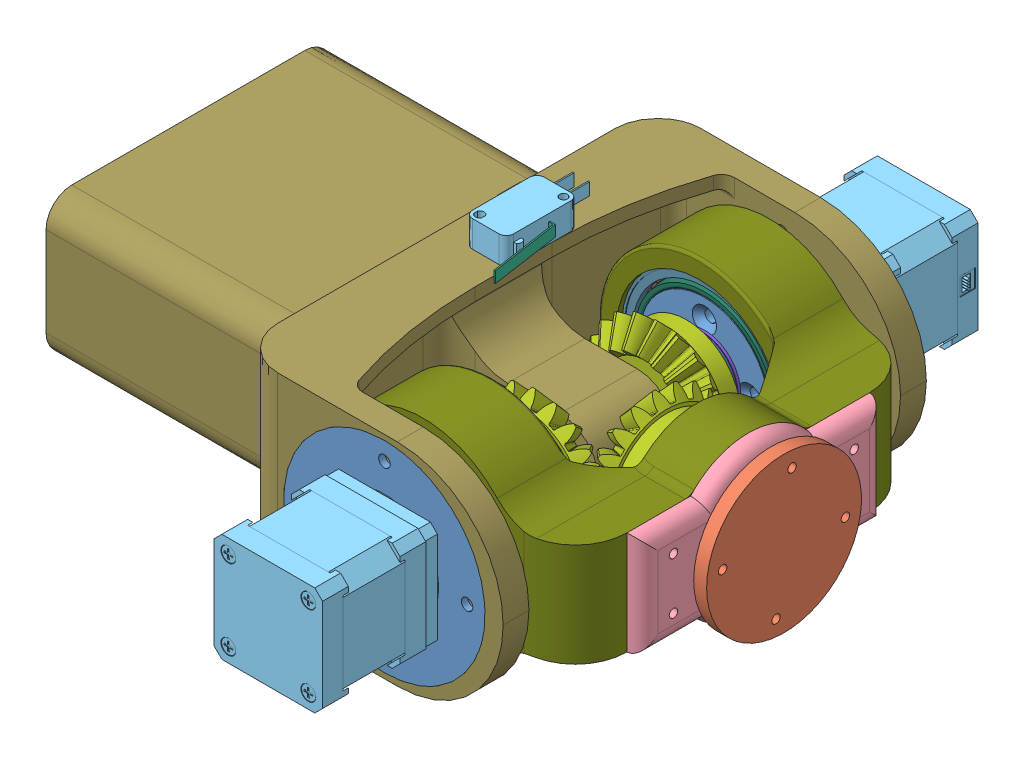
SolidWorks assembly Wrist assembly v4, configuration Default. Lengths in mm.
Overall size (231 102.6 254).
236 component instances, 25 part files, 63 mates.
Components (placement in the parent):
- Motor sleeve-1: Motor sleeve [Default] at (57.5488 50.2907 113.4481) x (0 0 -1) z (1 0 0) size (40 78 78)
- Motor sleeve-2: Motor sleeve [Default] at (57.5488 50.2907 -50.5519) x (0 0 1) z (-1 0 0) size (40 78 78)
- HK_1412-1: HK_1412 [Default] at (57.5488 50.2907 46.4481) x (0 0 -1) z (0.911021 -0.412359 0) size (12 20 20)
  - HK_1412_3-1: HK_1412_3 [Default] x (1 0 0) z (0 -0.382683 0.92388) size (7.3 2 2)
  - HK_1412_3-2: HK_1412_3 [Default] x (1 0 0) z (0 -0.707107 0.707107) size (7.3 2 2)
  - HK_1412_3-3: HK_1412_3 [Default] x (1 0 0) z (0 -0.92388 0.382683) size (7.3 2 2)
  - HK_1412_3-4: HK_1412_3 [Default] x (1 0 0) z (0 -1 0) size (7.3 2 2)
  - HK_1412_3-5: HK_1412_3 [Default] x (1 0 0) z (0 -0.92388 -0.382683) size (7.3 2 2)
  - HK_1412_3-6: HK_1412_3 [Default] x (1 0 0) z (0 -0.707107 -0.707107) size (7.3 2 2)
  - HK_1412_3-7: HK_1412_3 [Default] x (1 0 0) z (0 -0.382683 -0.92388) size (7.3 2 2)
  - HK_1412_3-8: HK_1412_3 [Default] x (1 0 0) z (0 0 -1) size (7.3 2 2)
  - HK_1412_3-9: HK_1412_3 [Default] x (1 0 0) z (0 0.382683 -0.92388) size (7.3 2 2)
  - HK_1412_3-10: HK_1412_3 [Default] x (1 0 0) z (0 0.707107 -0.707107) size (7.3 2 2)
  - HK_1412_3-11: HK_1412_3 [Default] x (1 0 0) z (0 0.92388 -0.382683) size (7.3 2 2)
  - HK_1412_3-12: HK_1412_3 [Default] x (1 0 0) z (0 1 0) size (7.3 2 2)
  - HK_1412_3-13: HK_1412_3 [Default] x (1 0 0) z (0 0.92388 0.382683) size (7.3 2 2)
  - HK_1412_3-14: HK_1412_3 [Default] x (1 0 0) z (0 0.707107 0.707107) size (7.3 2 2)
  - HK_1412_3-15: HK_1412_3 [Default] x (1 0 0) z (0 0.382683 0.92388) size (7.3 2 2)
  - HK_1412_3-16: HK_1412_3 [Default] at origin size (7.3 2 2)
  - HK_1412_20-1: HK_1412_20 [Default] x (1 0 0) z (0 -0.382683 0.92388) size (7.3 2 2)
  - HK_1412_20-2: HK_1412_20 [Default] x (1 0 0) z (0 -0.707107 0.707107) size (7.3 2 2)
  - HK_1412_20-3: HK_1412_20 [Default] x (1 0 0) z (0 -0.92388 0.382683) size (7.3 2 2)
  - HK_1412_20-4: HK_1412_20 [Default] x (1 0 0) z (0 -1 0) size (7.3 2 2)
  - HK_1412_20-5: HK_1412_20 [Default] x (1 0 0) z (0 -0.92388 -0.382683) size (7.3 2 2)
  - HK_1412_20-6: HK_1412_20 [Default] x (1 0 0) z (0 -0.707107 -0.707107) size (7.3 2 2)
  - HK_1412_20-7: HK_1412_20 [Default] x (1 0 0) z (0 -0.382683 -0.92388) size (7.3 2 2)
  - HK_1412_20-8: HK_1412_20 [Default] x (1 0 0) z (0 0 -1) size (7.3 2 2)
  - HK_1412_20-9: HK_1412_20 [Default] x (1 0 0) z (0 0.382683 -0.92388) size (7.3 2 2)
  - HK_1412_20-10: HK_1412_20 [Default] x (1 0 0) z (0 0.707107 -0.707107) size (7.3 2 2)
  - HK_1412_20-11: HK_1412_20 [Default] x (1 0 0) z (0 0.92388 -0.382683) size (7.3 2 2)
  - HK_1412_20-12: HK_1412_20 [Default] x (1 0 0) z (0 1 0) size (7.3 2 2)
  - HK_1412_20-13: HK_1412_20 [Default] x (1 0 0) z (0 0.92388 0.382683) size (7.3 2 2)
  - HK_1412_20-14: HK_1412_20 [Default] x (1 0 0) z (0 0.707107 0.707107) size (7.3 2 2)
  - HK_1412_20-15: HK_1412_20 [Default] x (1 0 0) z (0 0.382683 0.92388) size (7.3 2 2)
  - HK_1412_20-16: HK_1412_20 [Default] at origin size (7.3 2 2)
  - HK_1412_37-1: HK_1412_37 [Default] at origin size (12 20 20)
- HK_1412-2: HK_1412 [Default] at (57.5488 50.2907 28.4481) x (0 0 -1) z (0.122911 0.992418 0) size (12 20 20)
  - HK_1412_3-1: HK_1412_3 [Default] x (1 0 0) z (0 -0.382683 0.92388) size (7.3 2 2)
  - HK_1412_3-2: HK_1412_3 [Default] x (1 0 0) z (0 -0.707107 0.707107) size (7.3 2 2)
  - HK_1412_3-3: HK_1412_3 [Default] x (1 0 0) z (0 -0.92388 0.382683) size (7.3 2 2)
  - HK_1412_3-4: HK_1412_3 [Default] x (1 0 0) z (0 -1 0) size (7.3 2 2)
  - HK_1412_3-5: HK_1412_3 [Default] x (1 0 0) z (0 -0.92388 -0.382683) size (7.3 2 2)
  - HK_1412_3-6: HK_1412_3 [Default] x (1 0 0) z (0 -0.707107 -0.707107) size (7.3 2 2)
  - HK_1412_3-7: HK_1412_3 [Default] x (1 0 0) z (0 -0.382683 -0.92388) size (7.3 2 2)
  - HK_1412_3-8: HK_1412_3 [Default] x (1 0 0) z (0 0 -1) size (7.3 2 2)
  - HK_1412_3-9: HK_1412_3 [Default] x (1 0 0) z (0 0.382683 -0.92388) size (7.3 2 2)
  - HK_1412_3-10: HK_1412_3 [Default] x (1 0 0) z (0 0.707107 -0.707107) size (7.3 2 2)
  - HK_1412_3-11: HK_1412_3 [Default] x (1 0 0) z (0 0.92388 -0.382683) size (7.3 2 2)
  - HK_1412_3-12: HK_1412_3 [Default] x (1 0 0) z (0 1 0) size (7.3 2 2)
  - HK_1412_3-13: HK_1412_3 [Default] x (1 0 0) z (0 0.92388 0.382683) size (7.3 2 2)
  - HK_1412_3-14: HK_1412_3 [Default] x (1 0 0) z (0 0.707107 0.707107) size (7.3 2 2)
  - HK_1412_3-15: HK_1412_3 [Default] x (1 0 0) z (0 0.382683 0.92388) size (7.3 2 2)
  - HK_1412_3-16: HK_1412_3 [Default] at origin size (7.3 2 2)
  - HK_1412_20-1: HK_1412_20 [Default] x (1 0 0) z (0 -0.382683 0.92388) size (7.3 2 2)
  - HK_1412_20-2: HK_1412_20 [Default] x (1 0 0) z (0 -0.707107 0.707107) size (7.3 2 2)
  - HK_1412_20-3: HK_1412_20 [Default] x (1 0 0) z (0 -0.92388 0.382683) size (7.3 2 2)
  - HK_1412_20-4: HK_1412_20 [Default] x (1 0 0) z (0 -1 0) size (7.3 2 2)
  - HK_1412_20-5: HK_1412_20 [Default] x (1 0 0) z (0 -0.92388 -0.382683) size (7.3 2 2)
  - HK_1412_20-6: HK_1412_20 [Default] x (1 0 0) z (0 -0.707107 -0.707107) size (7.3 2 2)
  - HK_1412_20-7: HK_1412_20 [Default] x (1 0 0) z (0 -0.382683 -0.92388) size (7.3 2 2)
  - HK_1412_20-8: HK_1412_20 [Default] x (1 0 0) z (0 0 -1) size (7.3 2 2)
  - HK_1412_20-9: HK_1412_20 [Default] x (1 0 0) z (0 0.382683 -0.92388) size (7.3 2 2)
  - HK_1412_20-10: HK_1412_20 [Default] x (1 0 0) z (0 0.707107 -0.707107) size (7.3 2 2)
  - HK_1412_20-11: HK_1412_20 [Default] x (1 0 0) z (0 0.92388 -0.382683) size (7.3 2 2)
  - HK_1412_20-12: HK_1412_20 [Default] x (1 0 0) z (0 1 0) size (7.3 2 2)
  - HK_1412_20-13: HK_1412_20 [Default] x (1 0 0) z (0 0.92388 0.382683) size (7.3 2 2)
  - HK_1412_20-14: HK_1412_20 [Default] x (1 0 0) z (0 0.707107 0.707107) size (7.3 2 2)
  - HK_1412_20-15: HK_1412_20 [Default] x (1 0 0) z (0 0.382683 0.92388) size (7.3 2 2)
  - HK_1412_20-16: HK_1412_20 [Default] at origin size (7.3 2 2)
  - HK_1412_37-1: HK_1412_37 [Default] at origin size (12 20 20)
- 17HS15-1684D-HG10-AR3-2: 17HS15-1684D-HG10-AR3 [Default] at (57.5488 50.2907 -55.5519) size (42.88 42 103.5)
- 17HS15-1684D-HG10-AR3-3: 17HS15-1684D-HG10-AR3 [Default] at (57.5488 50.2907 118.4481) x (-1 0 0) z (0 0 -1) size (42.88 42 103.5)
- shaft-1: shaft [Default] at (57.5488 50.2907 -12.0519) x (0 0 1) z (0.708325 0.705887 0) size (42 17 17)
- shaft-2: shaft [Default] at (57.5488 50.2907 74.9481) x (0 0 -1) z (-0.905823 0.423655 0) size (42 17 17)
- AXK_1528___AS_1528___AS_1528-2: AXK_1528___AS_1528___AS_1528 [Default] at (57.5488 50.2907 71.4481) x (0 0 -1) z (0.812919 0.582377 0) size (4 28 28)
  - AXK_1528___AS_1528___AS_1528_3-1: AXK_1528___AS_1528___AS_1528_3 [Default] x (1 0 0) z (0 -0.309017 0.951057) size (2 5 2)
  - AXK_1528___AS_1528___AS_1528_3-2: AXK_1528___AS_1528___AS_1528_3 [Default] x (1 0 0) z (0 -0.587785 0.809017) size (2 5 2)
  - AXK_1528___AS_1528___AS_1528_3-3: AXK_1528___AS_1528___AS_1528_3 [Default] x (1 0 0) z (0 -0.809017 0.587785) size (2 5 2)
  - AXK_1528___AS_1528___AS_1528_3-4: AXK_1528___AS_1528___AS_1528_3 [Default] x (1 0 0) z (0 -0.951057 0.309017) size (2 5 2)
  - AXK_1528___AS_1528___AS_1528_3-5: AXK_1528___AS_1528___AS_1528_3 [Default] x (1 0 0) z (0 -1 0) size (2 5 2)
  - AXK_1528___AS_1528___AS_1528_3-6: AXK_1528___AS_1528___AS_1528_3 [Default] x (1 0 0) z (0 -0.951057 -0.309017) size (2 5 2)
  - AXK_1528___AS_1528___AS_1528_3-7: AXK_1528___AS_1528___AS_1528_3 [Default] x (1 0 0) z (0 -0.809017 -0.587785) size (2 5 2)
  - AXK_1528___AS_1528___AS_1528_3-8: AXK_1528___AS_1528___AS_1528_3 [Default] x (1 0 0) z (0 -0.587785 -0.809017) size (2 5 2)
  - AXK_1528___AS_1528___AS_1528_3-9: AXK_1528___AS_1528___AS_1528_3 [Default] x (1 0 0) z (0 -0.309017 -0.951057) size (2 5 2)
  - AXK_1528___AS_1528___AS_1528_3-10: AXK_1528___AS_1528___AS_1528_3 [Default] x (1 0 0) z (0 0 -1) size (2 5 2)
  - AXK_1528___AS_1528___AS_1528_3-11: AXK_1528___AS_1528___AS_1528_3 [Default] x (1 0 0) z (0 0.309017 -0.951057) size (2 5 2)
  - AXK_1528___AS_1528___AS_1528_3-12: AXK_1528___AS_1528___AS_1528_3 [Default] x (1 0 0) z (0 0.587785 -0.809017) size (2 5 2)
  - AXK_1528___AS_1528___AS_1528_3-13: AXK_1528___AS_1528___AS_1528_3 [Default] x (1 0 0) z (0 0.809017 -0.587785) size (2 5 2)
  - AXK_1528___AS_1528___AS_1528_3-14: AXK_1528___AS_1528___AS_1528_3 [Default] x (1 0 0) z (0 0.951057 -0.309017) size (2 5 2)
  - AXK_1528___AS_1528___AS_1528_3-15: AXK_1528___AS_1528___AS_1528_3 [Default] x (1 0 0) z (0 1 0) size (2 5 2)
  - AXK_1528___AS_1528___AS_1528_3-16: AXK_1528___AS_1528___AS_1528_3 [Default] x (1 0 0) z (0 0.951057 0.309017) size (2 5 2)
  - AXK_1528___AS_1528___AS_1528_3-17: AXK_1528___AS_1528___AS_1528_3 [Default] x (1 0 0) z (0 0.809017 0.587785) size (2 5 2)
  - AXK_1528___AS_1528___AS_1528_3-18: AXK_1528___AS_1528___AS_1528_3 [Default] x (1 0 0) z (0 0.587785 0.809017) size (2 5 2)
  - AXK_1528___AS_1528___AS_1528_3-19: AXK_1528___AS_1528___AS_1528_3 [Default] x (1 0 0) z (0 0.309017 0.951057) size (2 5 2)
  - AXK_1528___AS_1528___AS_1528_3-20: AXK_1528___AS_1528___AS_1528_3 [Default] at origin size (2 5 2)
  - AXK_1528___AS_1528___AS_1528_24-1: AXK_1528___AS_1528___AS_1528_24 [Default] at origin size (1 28 28)
  - AXK_1528___AS_1528___AS_1528_26-1: AXK_1528___AS_1528___AS_1528_26 [Default] at origin size (1 28 28)
  - AXK_1528___AS_1528___AS_1528_28-1: AXK_1528___AS_1528___AS_1528_28 [Default] at origin size (1.6 28 28)
- 2mm spacer-1: 2mm spacer [Default] at (57.5488 50.2907 66.4481) x (0.999741 0.022777 0) z (0 0 1) size (28 28 1.5)
- AXK_1528___AS_1528___AS_1528-3: AXK_1528___AS_1528___AS_1528 [Default] at (57.5488 50.2907 -8.5519) x (0 0 -1) z (0.999526 -0.030788 0) size (4 28 28)
  - AXK_1528___AS_1528___AS_1528_3-1: AXK_1528___AS_1528___AS_1528_3 [Default] x (1 0 0) z (0 -0.309017 0.951057) size (2 5 2)
  - AXK_1528___AS_1528___AS_1528_3-2: AXK_1528___AS_1528___AS_1528_3 [Default] x (1 0 0) z (0 -0.587785 0.809017) size (2 5 2)
  - AXK_1528___AS_1528___AS_1528_3-3: AXK_1528___AS_1528___AS_1528_3 [Default] x (1 0 0) z (0 -0.809017 0.587785) size (2 5 2)
  - AXK_1528___AS_1528___AS_1528_3-4: AXK_1528___AS_1528___AS_1528_3 [Default] x (1 0 0) z (0 -0.951057 0.309017) size (2 5 2)
  - AXK_1528___AS_1528___AS_1528_3-5: AXK_1528___AS_1528___AS_1528_3 [Default] x (1 0 0) z (0 -1 0) size (2 5 2)
  - AXK_1528___AS_1528___AS_1528_3-6: AXK_1528___AS_1528___AS_1528_3 [Default] x (1 0 0) z (0 -0.951057 -0.309017) size (2 5 2)
  - AXK_1528___AS_1528___AS_1528_3-7: AXK_1528___AS_1528___AS_1528_3 [Default] x (1 0 0) z (0 -0.809017 -0.587785) size (2 5 2)
  - AXK_1528___AS_1528___AS_1528_3-8: AXK_1528___AS_1528___AS_1528_3 [Default] x (1 0 0) z (0 -0.587785 -0.809017) size (2 5 2)
  - AXK_1528___AS_1528___AS_1528_3-9: AXK_1528___AS_1528___AS_1528_3 [Default] x (1 0 0) z (0 -0.309017 -0.951057) size (2 5 2)
  - AXK_1528___AS_1528___AS_1528_3-10: AXK_1528___AS_1528___AS_1528_3 [Default] x (1 0 0) z (0 0 -1) size (2 5 2)
  - AXK_1528___AS_1528___AS_1528_3-11: AXK_1528___AS_1528___AS_1528_3 [Default] x (1 0 0) z (0 0.309017 -0.951057) size (2 5 2)
  - AXK_1528___AS_1528___AS_1528_3-12: AXK_1528___AS_1528___AS_1528_3 [Default] x (1 0 0) z (0 0.587785 -0.809017) size (2 5 2)
  - AXK_1528___AS_1528___AS_1528_3-13: AXK_1528___AS_1528___AS_1528_3 [Default] x (1 0 0) z (0 0.809017 -0.587785) size (2 5 2)
  - AXK_1528___AS_1528___AS_1528_3-14: AXK_1528___AS_1528___AS_1528_3 [Default] x (1 0 0) z (0 0.951057 -0.309017) size (2 5 2)
  - AXK_1528___AS_1528___AS_1528_3-15: AXK_1528___AS_1528___AS_1528_3 [Default] x (1 0 0) z (0 1 0) size (2 5 2)
  - AXK_1528___AS_1528___AS_1528_3-16: AXK_1528___AS_1528___AS_1528_3 [Default] x (1 0 0) z (0 0.951057 0.309017) size (2 5 2)
  - AXK_1528___AS_1528___AS_1528_3-17: AXK_1528___AS_1528___AS_1528_3 [Default] x (1 0 0) z (0 0.809017 0.587785) size (2 5 2)
  - AXK_1528___AS_1528___AS_1528_3-18: AXK_1528___AS_1528___AS_1528_3 [Default] x (1 0 0) z (0 0.587785 0.809017) size (2 5 2)
  - AXK_1528___AS_1528___AS_1528_3-19: AXK_1528___AS_1528___AS_1528_3 [Default] x (1 0 0) z (0 0.309017 0.951057) size (2 5 2)
  - AXK_1528___AS_1528___AS_1528_3-20: AXK_1528___AS_1528___AS_1528_3 [Default] at origin size (2 5 2)
  - AXK_1528___AS_1528___AS_1528_24-1: AXK_1528___AS_1528___AS_1528_24 [Default] at origin size (1 28 28)
  - AXK_1528___AS_1528___AS_1528_26-1: AXK_1528___AS_1528___AS_1528_26 [Default] at origin size (1 28 28)
  - AXK_1528___AS_1528___AS_1528_28-1: AXK_1528___AS_1528___AS_1528_28 [Default] at origin size (1.6 28 28)
- 2mm spacer-2: 2mm spacer [Default] at (57.5488 50.2907 -5.0519) x (0.999526 -0.030788 0) z (0 0 1) size (28 28 1.5)
- Wrist input frame_combined-2: Wrist input frame_combined [Default] at (-20.9706 -62.2225 152.6176) x (-1 0 0) z (0 0 -1) size (204 82 164)
- NKI_50_25-1: NKI_50_25 [Default] at (57.5488 50.2907 -10.5519) x (0 0 -1) z (0.995738 -0.092229 0) size (25 68.42 68)
  - NKI_50_25_37-1: NKI_50_25_37 [Default] x (1 0 0) z (0 -0.189251 0.981929) size (18.8 3.5 3.5)
  - NKI_50_25_37-2: NKI_50_25_37 [Default] x (1 0 0) z (0 -0.371662 0.928368) size (18.8 3.5 3.5)
  - NKI_50_25_37-3: NKI_50_25_37 [Default] x (1 0 0) z (0 -0.540641 0.841254) size (18.8 3.5 3.5)
  - NKI_50_25_37-4: NKI_50_25_37 [Default] x (1 0 0) z (0 -0.690079 0.723734) size (18.8 3.5 3.5)
  - NKI_50_25_37-5: NKI_50_25_37 [Default] x (1 0 0) z (0 -0.814576 0.580057) size (18.8 3.5 3.5)
  - NKI_50_25_37-6: NKI_50_25_37 [Default] x (1 0 0) z (0 -0.909632 0.415415) size (18.8 3.5 3.5)
  - NKI_50_25_37-7: NKI_50_25_37 [Default] x (1 0 0) z (0 -0.971812 0.235759) size (18.8 3.5 3.5)
  - NKI_50_25_37-8: NKI_50_25_37 [Default] x (1 0 0) z (0 -0.998867 0.047582) size (18.8 3.5 3.5)
  - NKI_50_25_37-9: NKI_50_25_37 [Default] x (1 0 0) z (0 -0.989821 -0.142315) size (18.8 3.5 3.5)
  - NKI_50_25_37-10: NKI_50_25_37 [Default] x (1 0 0) z (0 -0.945001 -0.327068) size (18.8 3.5 3.5)
  - NKI_50_25_37-11: NKI_50_25_37 [Default] x (1 0 0) z (0 -0.866025 -0.5) size (18.8 3.5 3.5)
  - NKI_50_25_37-12: NKI_50_25_37 [Default] x (1 0 0) z (0 -0.75575 -0.654861) size (18.8 3.5 3.5)
  - NKI_50_25_37-13: NKI_50_25_37 [Default] x (1 0 0) z (0 -0.618159 -0.786053) size (18.8 3.5 3.5)
  - NKI_50_25_37-14: NKI_50_25_37 [Default] x (1 0 0) z (0 -0.458227 -0.888835) size (18.8 3.5 3.5)
  - NKI_50_25_37-15: NKI_50_25_37 [Default] x (1 0 0) z (0 -0.281733 -0.959493) size (18.8 3.5 3.5)
  - NKI_50_25_37-16: NKI_50_25_37 [Default] x (1 0 0) z (0 -0.095056 -0.995472) size (18.8 3.5 3.5)
  - NKI_50_25_37-17: NKI_50_25_37 [Default] x (1 0 0) z (0 0.095056 -0.995472) size (18.8 3.5 3.5)
  - NKI_50_25_37-18: NKI_50_25_37 [Default] x (1 0 0) z (0 0.281733 -0.959493) size (18.8 3.5 3.5)
  - NKI_50_25_37-19: NKI_50_25_37 [Default] x (1 0 0) z (0 0.458227 -0.888835) size (18.8 3.5 3.5)
  - NKI_50_25_37-20: NKI_50_25_37 [Default] x (1 0 0) z (0 0.618159 -0.786053) size (18.8 3.5 3.5)
  - NKI_50_25_37-21: NKI_50_25_37 [Default] x (1 0 0) z (0 0.75575 -0.654861) size (18.8 3.5 3.5)
  - NKI_50_25_37-22: NKI_50_25_37 [Default] x (1 0 0) z (0 0.866025 -0.5) size (18.8 3.5 3.5)
  - NKI_50_25_37-23: NKI_50_25_37 [Default] x (1 0 0) z (0 0.945001 -0.327068) size (18.8 3.5 3.5)
  - NKI_50_25_37-24: NKI_50_25_37 [Default] x (1 0 0) z (0 0.989821 -0.142315) size (18.8 3.5 3.5)
  - NKI_50_25_37-25: NKI_50_25_37 [Default] x (1 0 0) z (0 0.998867 0.047582) size (18.8 3.5 3.5)
  - NKI_50_25_37-26: NKI_50_25_37 [Default] x (1 0 0) z (0 0.971812 0.235759) size (18.8 3.5 3.5)
  - NKI_50_25_37-27: NKI_50_25_37 [Default] x (1 0 0) z (0 0.909632 0.415415) size (18.8 3.5 3.5)
  - NKI_50_25_37-28: NKI_50_25_37 [Default] x (1 0 0) z (0 0.814576 0.580057) size (18.8 3.5 3.5)
  - NKI_50_25_37-29: NKI_50_25_37 [Default] x (1 0 0) z (0 0.690079 0.723734) size (18.8 3.5 3.5)
  - NKI_50_25_37-30: NKI_50_25_37 [Default] x (1 0 0) z (0 0.540641 0.841254) size (18.8 3.5 3.5)
  - NKI_50_25_37-31: NKI_50_25_37 [Default] x (1 0 0) z (0 0.371662 0.928368) size (18.8 3.5 3.5)
  - NKI_50_25_37-32: NKI_50_25_37 [Default] x (1 0 0) z (0 0.189251 0.981929) size (18.8 3.5 3.5)
  - NKI_50_25_37-33: NKI_50_25_37 [Default] at origin size (18.8 3.5 3.5)
  - NKI_50_25_71-1: NKI_50_25_71 [Default] at origin size (25 68.42 68)
  - NKI_50_25_73-1: NKI_50_25_73 [Default] at origin size (25 55 55)
- NKI_50_25-2: NKI_50_25 [Default] at (57.5488 50.2907 98.4481) x (0 0 -1) z (0.982967 -0.183783 0) size (25 68.42 68)
  - NKI_50_25_37-1: NKI_50_25_37 [Default] x (1 0 0) z (0 -0.189251 0.981929) size (18.8 3.5 3.5)
  - NKI_50_25_37-2: NKI_50_25_37 [Default] x (1 0 0) z (0 -0.371662 0.928368) size (18.8 3.5 3.5)
  - NKI_50_25_37-3: NKI_50_25_37 [Default] x (1 0 0) z (0 -0.540641 0.841254) size (18.8 3.5 3.5)
  - NKI_50_25_37-4: NKI_50_25_37 [Default] x (1 0 0) z (0 -0.690079 0.723734) size (18.8 3.5 3.5)
  - NKI_50_25_37-5: NKI_50_25_37 [Default] x (1 0 0) z (0 -0.814576 0.580057) size (18.8 3.5 3.5)
  - NKI_50_25_37-6: NKI_50_25_37 [Default] x (1 0 0) z (0 -0.909632 0.415415) size (18.8 3.5 3.5)
  - NKI_50_25_37-7: NKI_50_25_37 [Default] x (1 0 0) z (0 -0.971812 0.235759) size (18.8 3.5 3.5)
  - NKI_50_25_37-8: NKI_50_25_37 [Default] x (1 0 0) z (0 -0.998867 0.047582) size (18.8 3.5 3.5)
  - NKI_50_25_37-9: NKI_50_25_37 [Default] x (1 0 0) z (0 -0.989821 -0.142315) size (18.8 3.5 3.5)
  - NKI_50_25_37-10: NKI_50_25_37 [Default] x (1 0 0) z (0 -0.945001 -0.327068) size (18.8 3.5 3.5)
  - NKI_50_25_37-11: NKI_50_25_37 [Default] x (1 0 0) z (0 -0.866025 -0.5) size (18.8 3.5 3.5)
  - NKI_50_25_37-12: NKI_50_25_37 [Default] x (1 0 0) z (0 -0.75575 -0.654861) size (18.8 3.5 3.5)
  - NKI_50_25_37-13: NKI_50_25_37 [Default] x (1 0 0) z (0 -0.618159 -0.786053) size (18.8 3.5 3.5)
  - NKI_50_25_37-14: NKI_50_25_37 [Default] x (1 0 0) z (0 -0.458227 -0.888835) size (18.8 3.5 3.5)
  - NKI_50_25_37-15: NKI_50_25_37 [Default] x (1 0 0) z (0 -0.281733 -0.959493) size (18.8 3.5 3.5)
  - NKI_50_25_37-16: NKI_50_25_37 [Default] x (1 0 0) z (0 -0.095056 -0.995472) size (18.8 3.5 3.5)
  - NKI_50_25_37-17: NKI_50_25_37 [Default] x (1 0 0) z (0 0.095056 -0.995472) size (18.8 3.5 3.5)
  - NKI_50_25_37-18: NKI_50_25_37 [Default] x (1 0 0) z (0 0.281733 -0.959493) size (18.8 3.5 3.5)
  - NKI_50_25_37-19: NKI_50_25_37 [Default] x (1 0 0) z (0 0.458227 -0.888835) size (18.8 3.5 3.5)
  - NKI_50_25_37-20: NKI_50_25_37 [Default] x (1 0 0) z (0 0.618159 -0.786053) size (18.8 3.5 3.5)
  - NKI_50_25_37-21: NKI_50_25_37 [Default] x (1 0 0) z (0 0.75575 -0.654861) size (18.8 3.5 3.5)
  - NKI_50_25_37-22: NKI_50_25_37 [Default] x (1 0 0) z (0 0.866025 -0.5) size (18.8 3.5 3.5)
  - NKI_50_25_37-23: NKI_50_25_37 [Default] x (1 0 0) z (0 0.945001 -0.327068) size (18.8 3.5 3.5)
  - NKI_50_25_37-24: NKI_50_25_37 [Default] x (1 0 0) z (0 0.989821 -0.142315) size (18.8 3.5 3.5)
  - NKI_50_25_37-25: NKI_50_25_37 [Default] x (1 0 0) z (0 0.998867 0.047582) size (18.8 3.5 3.5)
  - NKI_50_25_37-26: NKI_50_25_37 [Default] x (1 0 0) z (0 0.971812 0.235759) size (18.8 3.5 3.5)
  - NKI_50_25_37-27: NKI_50_25_37 [Default] x (1 0 0) z (0 0.909632 0.415415) size (18.8 3.5 3.5)
  - NKI_50_25_37-28: NKI_50_25_37 [Default] x (1 0 0) z (0 0.814576 0.580057) size (18.8 3.5 3.5)
  - NKI_50_25_37-29: NKI_50_25_37 [Default] x (1 0 0) z (0 0.690079 0.723734) size (18.8 3.5 3.5)
  - NKI_50_25_37-30: NKI_50_25_37 [Default] x (1 0 0) z (0 0.540641 0.841254) size (18.8 3.5 3.5)
  - NKI_50_25_37-31: NKI_50_25_37 [Default] x (1 0 0) z (0 0.371662 0.928368) size (18.8 3.5 3.5)
  - NKI_50_25_37-32: NKI_50_25_37 [Default] x (1 0 0) z (0 0.189251 0.981929) size (18.8 3.5 3.5)
  - NKI_50_25_37-33: NKI_50_25_37 [Default] at origin size (18.8 3.5 3.5)
  - NKI_50_25_71-1: NKI_50_25_71 [Default] at origin size (25 68.42 68)
  - NKI_50_25_73-1: NKI_50_25_73 [Default] at origin size (25 55 55)
- Wrist output frame-1: Wrist output frame [Default] at (57.5488 50.2907 98.4481) x (0 0 -1) z (0 -1 0) size (134 102 78)
- 7203_BEY-3: 7203_BEY [Default] at (108.5488 50.2907 31.4481) x (-1 0 0) z (0 -0.984874 -0.173274) size (12 40 40)
  - 7203_BEY_3-1: 7203_BEY_3 [Default] x (1 0 0) z (0 -0.587785 0.809017) size (7.14 7.14 7.14)
  - 7203_BEY_3-2: 7203_BEY_3 [Default] x (1 0 0) z (0 -0.951057 0.309017) size (7.14 7.14 7.14)
  - 7203_BEY_3-3: 7203_BEY_3 [Default] x (1 0 0) z (0 -0.951057 -0.309017) size (7.14 7.14 7.14)
  - 7203_BEY_3-4: 7203_BEY_3 [Default] x (1 0 0) z (0 -0.587785 -0.809017) size (7.14 7.14 7.14)
  - 7203_BEY_3-5: 7203_BEY_3 [Default] x (1 0 0) z (0 0 -1) size (7.14 7.14 7.14)
  - 7203_BEY_3-6: 7203_BEY_3 [Default] x (1 0 0) z (0 0.587785 -0.809017) size (7.14 7.14 7.14)
  - 7203_BEY_3-7: 7203_BEY_3 [Default] x (1 0 0) z (0 0.951057 -0.309017) size (7.14 7.14 7.14)
  - 7203_BEY_3-8: 7203_BEY_3 [Default] x (1 0 0) z (0 0.951057 0.309017) size (7.14 7.14 7.14)
  - 7203_BEY_3-9: 7203_BEY_3 [Default] x (1 0 0) z (0 0.587785 0.809017) size (7.14 7.14 7.14)
  - 7203_BEY_3-10: 7203_BEY_3 [Default] at origin size (7.14 7.14 7.14)
  - 7203_BEY_14-1: 7203_BEY_14 [Default] at origin size (12 40 40)
  - 7203_BEY_16-1: 7203_BEY_16 [Default] at origin size (12 26.25 26.25)
- 7203_BEY-4: 7203_BEY [Default] at (108.5488 50.2907 31.4481) x (1 0 0) z (0 0.327595 0.944818) size (12 40 40)
  - 7203_BEY_3-1: 7203_BEY_3 [Default] x (1 0 0) z (0 -0.587785 0.809017) size (7.14 7.14 7.14)
  - 7203_BEY_3-2: 7203_BEY_3 [Default] x (1 0 0) z (0 -0.951057 0.309017) size (7.14 7.14 7.14)
  - 7203_BEY_3-3: 7203_BEY_3 [Default] x (1 0 0) z (0 -0.951057 -0.309017) size (7.14 7.14 7.14)
  - 7203_BEY_3-4: 7203_BEY_3 [Default] x (1 0 0) z (0 -0.587785 -0.809017) size (7.14 7.14 7.14)
  - 7203_BEY_3-5: 7203_BEY_3 [Default] x (1 0 0) z (0 0 -1) size (7.14 7.14 7.14)
  - 7203_BEY_3-6: 7203_BEY_3 [Default] x (1 0 0) z (0 0.587785 -0.809017) size (7.14 7.14 7.14)
  - 7203_BEY_3-7: 7203_BEY_3 [Default] x (1 0 0) z (0 0.951057 -0.309017) size (7.14 7.14 7.14)
  - 7203_BEY_3-8: 7203_BEY_3 [Default] x (1 0 0) z (0 0.951057 0.309017) size (7.14 7.14 7.14)
  - 7203_BEY_3-9: 7203_BEY_3 [Default] x (1 0 0) z (0 0.587785 0.809017) size (7.14 7.14 7.14)
  - 7203_BEY_3-10: 7203_BEY_3 [Default] at origin size (7.14 7.14 7.14)
  - 7203_BEY_14-1: 7203_BEY_14 [Default] at origin size (12 40 40)
  - 7203_BEY_16-1: 7203_BEY_16 [Default] at origin size (12 26.25 26.25)
- Output shaft-1: Output shaft [Default] at (76.4988 50.2907 31.6124) x (0 -0.129395 -0.991593) z (1 0 0) size (60 60 52.05)
- 4mm spacer-1: 4mm spacer [Default] at (92.5488 50.2907 31.6124) x (0 -0.609252 -0.792977) z (1 0 0) size (26 26 4)
- Wrist output cap-1: Wrist output cap [Default] at (120.5488 50.2907 31.4481) x (0 0 -1) z (1 0 0) size (94 60 6.33)
- V_152_1C25-1: V_152_1C25 [Default] at (22.7488 96.4407 9.2481) x (0 0 -1) z (0 -1 0) size (48.18 24.9 10.3)
  - V_152_1C25_BASE-1: V_152_1C25_BASE [Default] at origin size (37.8 20.43 10.3)
  - V_152_1C25_ACTUATOR-1: V_152_1C25_ACTUATOR [Default] at (-8.6 2.8 -0.2) size (27.28 6.1 4.3)
- V_152_1C25-2: V_152_1C25 [Default] at (22.7488 4.1407 9.2481) x (0 0 -1) z (0 -1 0) size (48.18 24.9 10.3)
  - V_152_1C25_BASE-1: V_152_1C25_BASE [Default] at origin size (37.8 20.43 10.3)
  - V_152_1C25_ACTUATOR-1: V_152_1C25_ACTUATOR [Default] at (-8.6 2.8 -0.2) size (27.28 6.1 4.3)
- straight miter gear_am-1: straight miter gear_am [A 1C 4MYKW25020] at (57.5488 50.2907 3.8222) x (0 0 1) z (-0.708325 -0.705887 0) size (19.66 53.34 53.34)
- straight miter gear_am-2: straight miter gear_am [A 1C 4MYKW25020] at (57.5488 50.2907 59.074) x (0 0 -1) z (0.905823 -0.423655 0) size (19.66 53.34 53.34)
- straight miter gear_am-3: straight miter gear_am [A 1C 4MYKW25020] at (85.1747 50.2907 31.6124) x (-1 0 0) z (0 -0.129395 -0.991593) size (19.66 53.34 53.34)
Mates (geometry in assembly coordinates):
- Concentric10: concentric aligned: cylinder of Motor sleeve-2 through (57.5488 50.2907 -114.6552) axis (0 0 -1) radius 21; cylinder of 17HS15-1684D-HG10-AR3-2 through (57.5488 50.2907 -15.5519) axis (0 0 -1) radius 21
- Concentric11: concentric aligned: cylinder of Motor sleeve-2 through (57.5488 67.7907 -10.5519) axis (0 0 1) radius 2.25; cylinder of 17HS15-1684D-HG10-AR3-2 through (57.5488 67.7907 -15.5519) axis (0 0 1) radius 2.25
- Concentric13: concentric aligned: cylinder of Motor sleeve-1 through (57.5488 50.2907 177.5515) axis (0 0 1) radius 21; cylinder of 17HS15-1684D-HG10-AR3-3 through (57.5488 50.2907 78.4481) axis (0 0 1) radius 21
- Concentric16: concentric aligned: cylinder of Motor sleeve-1 through (57.5488 67.7907 73.4481) axis (0 0 -1) radius 2.25; circle of 17HS15-1684D-HG10-AR3-3
- Coincident5: coincident anti-aligned: plane of Motor sleeve-2 through (57.5488 71.2907 -15.5519) normal (0 0 -1); plane of 17HS15-1684D-HG10-AR3-2 through (57.5488 50.2907 -15.5519) normal (0 0 1)
- Coincident7: coincident anti-aligned: plane of Motor sleeve-1 through (57.5488 71.2907 78.4481) normal (0 0 1); plane of 17HS15-1684D-HG10-AR3-3 through (57.5488 50.2907 78.4481) normal (0 0 -1)
- Concentric17: concentric aligned: cylinder of 17HS15-1684D-HG10-AR3-2 through (57.5488 50.2907 -8.2519) axis (0 0 -1) radius 4; cylinder of shaft-1 through (57.5488 50.2907 29.9481) axis (0 0 -1) radius 4
- Distance2: distance = 1.5 mm anti-aligned: plane of 17HS15-1684D-HG10-AR3-2 through (57.5488 50.2907 -13.5519) normal (0 0 1); plane of shaft-1 through (57.5488 50.2907 -12.0519) normal (0 0 -1)
- Concentric18: concentric aligned: cylinder of 17HS15-1684D-HG10-AR3-3 through (57.5488 50.2907 71.1481) axis (0 0 1) radius 4; cylinder of shaft-2 through (57.5488 50.2907 32.9481) axis (0 0 1) radius 4
- Distance3: distance = 1.5 mm anti-aligned: plane of 17HS15-1684D-HG10-AR3-3 through (57.5488 50.2907 76.4481) normal (0 0 -1); plane of shaft-2 through (57.5488 50.2907 74.9481) normal (0 0 1)
- Concentric20: concentric anti-aligned: cylinder of shaft-2 through (57.5488 50.2907 69.9481) axis (0 0 1) radius 7.5; circle of AXK_1528___AS_1528___AS_1528-2/AXK_1528___AS_1528___AS_1528_24-1
- Coincident10: coincident anti-aligned: plane of Motor sleeve-1 through (57.5488 58.7907 73.4481) normal (0 0 -1); plane of AXK_1528___AS_1528___AS_1528-2/AXK_1528___AS_1528___AS_1528_26-1 through (49.3956 61.6715 73.4481) normal (0 0 1)
- Concentric21: concentric anti-aligned: cylinder of shaft-2 through (57.5488 50.2907 32.9481) axis (0 0 1) radius 7.5; cylinder of 2mm spacer-1 through (57.5488 50.2907 67.9481) axis (0 0 -1) radius 7.5
- Coincident11: coincident anti-aligned: plane of shaft-2 through (57.5488 50.2907 67.9481) normal (0 0 -1); plane of 2mm spacer-1 through (57.5488 50.2907 67.9481) normal (0 0 1)
- Concentric23: concentric anti-aligned: cylinder of shaft-1 through (57.5488 50.2907 -7.0519) axis (0 0 -1) radius 7.5; cylinder of AXK_1528___AS_1528___AS_1528-3/AXK_1528___AS_1528___AS_1528_28-1 through (57.5488 50.2907 -9.3519) axis (0 0 1) radius 7.5
- Coincident14: coincident anti-aligned: plane of Motor sleeve-2 through (57.5488 58.7907 -10.5519) normal (0 0 1); plane of AXK_1528___AS_1528___AS_1528-3/AXK_1528___AS_1528___AS_1528_24-1 through (57.7797 57.7871 -10.5519) normal (0 0 -1)
- Concentric241: concentric aligned: cylinder of shaft-1 through (57.5488 50.2907 29.9481) axis (0 0 -1) radius 7.5; cylinder of 2mm spacer-2 through (57.5488 50.2907 -3.5519) axis (0 0 -1) radius 14
- Coincident15: coincident anti-aligned: plane of shaft-1 through (57.5488 50.2907 -5.0519) normal (0 0 1); plane of 2mm spacer-2 through (57.5488 50.2907 -5.0519) normal (0 0 -1)
- Concentric242: concentric aligned: cylinder of Motor sleeve-1 through (57.5488 50.2907 177.5515) axis (0 0 1) radius 25; cylinder of Wrist input frame_combined-2 through (57.5488 50.2907 34.4481) axis (0 0 1) radius 10
- Coincident17: coincident anti-aligned: plane of Motor sleeve-2 through (57.5488 76.2907 -48.0519) normal (0 0 1); plane of Wrist input frame_combined-2 through (57.5488 50.2907 -48.0519) normal (0 0 -1)
- Concentric243: concentric anti-aligned: cylinder of Motor sleeve-2 through (57.5488 50.2907 -114.6552) axis (0 0 -1) radius 25; circle of Wrist input frame_combined-2
- Concentric244: concentric aligned: cylinder of HK_1412-2/HK_1412_37-1 through (57.5488 50.2907 -21.5519) axis (0 0 -1) radius 7.5; cylinder of Wrist input frame_combined-2 through (57.5488 50.2907 28.4481) axis (0 0 -1) radius 10
- Coincident18: coincident anti-aligned: plane of HK_1412-2/HK_1412_37-1 through (48.4186 51.4215 28.4481) normal (0 0 1); plane of Wrist input frame_combined-2 through (57.5488 50.2907 28.4481) normal (0 0 -1)
- Concentric245: concentric anti-aligned: cylinder of HK_1412-1/HK_1412_37-1 through (57.5488 50.2907 -3.5519) axis (0 0 -1) radius 10; cylinder of Wrist input frame_combined-2 through (57.5488 50.2907 34.4481) axis (0 0 1) radius 10
- Coincident19: coincident anti-aligned: plane of HK_1412-1/HK_1412_37-1 through (60.6415 57.1233 34.4481) normal (0 0 -1); plane of Wrist input frame_combined-2 through (57.5488 50.2907 34.4481) normal (0 0 1)
- Concentric246: concentric anti-aligned: circle of Motor sleeve-2; circle of Wrist input frame_combined-2
- Concentric247: concentric anti-aligned: cylinder of Motor sleeve-1 through (57.5488 82.2907 113.4481) axis (0 0 1) radius 2.25; circle of Wrist input frame_combined-2
- Coincident20: coincident anti-aligned: plane of Motor sleeve-1 through (57.5488 76.2907 110.9481) normal (0 0 -1); plane of Wrist input frame_combined-2 through (57.5488 50.2907 110.9481) normal (0 0 1)
- Concentric248: concentric aligned: cylinder of Motor sleeve-2 through (57.5488 50.2907 -114.6552) axis (0 0 -1) radius 25; cylinder of NKI_50_25-1/NKI_50_25_73-1 through (57.5488 50.2907 -35.5519) axis (0 0 -1) radius 25
- Distance4: distance = 0 mm anti-aligned: plane of Motor sleeve-2 through (57.5488 75.2907 -35.5519) normal (0 0 1); plane of NKI_50_25-1/NKI_50_25_73-1 through (59.9099 75.7816 -35.5519) normal (0 0 -1)
- Concentric249: concentric anti-aligned: cylinder of Motor sleeve-1 through (57.5488 50.2907 177.5515) axis (0 0 1) radius 25; cylinder of NKI_50_25-2/NKI_50_25_73-1 through (57.5488 50.2907 73.4481) axis (0 0 -1) radius 25
- Distance5: distance = 0 mm anti-aligned: plane of Motor sleeve-1 through (57.5488 75.2907 98.4481) normal (0 0 -1); plane of NKI_50_25-2/NKI_50_25_73-1 through (62.4926 76.7325 98.4481) normal (0 0 1)
- Concentric250: concentric anti-aligned: cylinder of NKI_50_25-2/NKI_50_25_71-1 through (57.5488 50.2907 48.4481) axis (0 0 -1) radius 34; cylinder of Wrist output frame-1 through (57.5488 50.2907 73.4481) axis (0 0 1) radius 34
- Distance6: distance = 0 mm anti-aligned: plane of Wrist output frame-1 through (57.5488 50.2907 -10.5519) normal (0 0 -1); plane of NKI_50_25-1/NKI_50_25_71-1 through (60.6293 83.5483 -10.5519) normal (0 0 1)
- Concentric254: concentric aligned: cylinder of Wrist output frame-1 through (116.5498 50.2907 31.4481) axis (-1 0 0) radius 20; cylinder of 7203_BEY-3/7203_BEY_16-1 through (96.5488 50.2907 31.4481) axis (-1 0 0) radius 8.5
- Distance9: distance = 0 mm aligned: plane of 7203_BEY-3/7203_BEY_14-1 through (96.5488 53.4009 13.7696) normal (-1 0 0); plane of Wrist output frame-1 through (96.5488 50.2907 31.4481) normal (-1 0 0)
- Concentric255: concentric anti-aligned: cylinder of Wrist output frame-1 through (116.5498 50.2907 31.4481) axis (-1 0 0) radius 20; cylinder of 7203_BEY-4/7203_BEY_16-1 through (120.5488 50.2907 31.4481) axis (1 0 0) radius 8.5
- Coincident22: coincident anti-aligned: plane of 7203_BEY-3/7203_BEY_14-1 through (108.5488 53.6522 12.3416) normal (1 0 0); plane of 7203_BEY-4/7203_BEY_14-1 through (108.5488 68.6202 25.0928) normal (-1 0 0)
- Distance10: distance = 0 mm aligned: plane of Output shaft-1 through (96.5488 50.2907 31.6124) normal (-1 0 0); plane of Wrist output frame-1 through (96.5488 50.2907 31.4481) normal (-1 0 0)
- Concentric257: concentric aligned: cylinder of Output shaft-1 through (96.5488 50.2907 31.6124) axis (-1 0 0) radius 7.5; cylinder of 4mm spacer-1 through (96.5488 50.2907 31.6124) axis (-1 0 0) radius 7.5
- Coincident23: coincident anti-aligned: plane of 7203_BEY-3/7203_BEY_16-1 through (96.5488 51.8675 22.4858) normal (-1 0 0); plane of 4mm spacer-1 through (96.5488 50.2907 31.6124) normal (1 0 0)
- Parallel7: parallel aligned: plane of Wrist input frame_combined-2 through (-0.4512 91.2907 31.4481) normal (0 1 0)
- Parallel8: parallel anti-aligned: plane of Wrist input frame_combined-2 through (-4.4512 50.2907 31.4481) normal (-1 0 0)
- Concentric2584: concentric anti-aligned: cylinder of Wrist output frame-1 through (94.5488 50.2907 31.6124) axis (1 0 0) radius 17.9; cylinder of Output shaft-1 through (120.5488 50.2907 31.6124) axis (-1 0 0) radius 8.5
- Concentric2585: concentric anti-aligned: circle of Wrist output frame-1; circle of Wrist output cap-1
- Coincident27: coincident anti-aligned: plane of Wrist output frame-1 through (116.5488 50.2907 31.4481) normal (1 0 0); plane of Wrist output cap-1 through (116.5488 50.2907 31.4481) normal (-1 0 0)
- Coincident28: coincident anti-aligned: plane of Wrist input frame_combined-2 through (-0.4512 91.2907 31.4481) normal (0 1 0); plane of V_152_1C25-1/V_152_1C25_BASE-1 through (25.5488 91.2907 34.2481) normal (0 -1 0)
- Distance14: distance = 0 mm anti-aligned: plane of V_152_1C25-2/V_152_1C25_BASE-1 through (25.5488 9.2907 34.2481) normal (0 1 0); plane of Wrist input frame_combined-2 through (-0.4512 9.2907 31.4481) normal (0 -1 0)
- Distance24: distance = 0 mm aligned: plane of V_152_1C25-1/V_152_1C25_BASE-1 through (25.5488 91.2907 34.2481) normal (1 0 0); plane of Wrist input frame_combined-2 through (25.5488 86.2907 31.4481) normal (1 0 0)
- Distance25: distance = 57 mm aligned: plane of V_152_1C25-1/V_152_1C25_BASE-1 through (25.5488 91.2907 6.4481) normal (0 0 -1); plane of Wrist input frame_combined-2 through (-0.4512 9.2907 -50.5519) normal (0 0 -1)
- Distance26: distance = 0 mm aligned: plane of V_152_1C25-2/V_152_1C25_BASE-1 through (25.5488 -1.0093 34.2481) normal (1 0 0); plane of Wrist input frame_combined-2 through (25.5488 14.2907 31.4481) normal (1 0 0)
- Distance27: distance = 57 mm aligned: plane of V_152_1C25-2/V_152_1C25_BASE-1 through (25.5488 -1.0093 6.4481) normal (0 0 -1); plane of Wrist input frame_combined-2 through (-0.4512 9.2907 -50.5519) normal (0 0 -1)
- Concentric2586: concentric anti-aligned: cylinder of shaft-1 through (57.5488 50.2907 29.9481) axis (0 0 -1) radius 7.5; cylinder of straight miter gear_am-1 through (57.5488 50.2907 -3.5519) axis (0 0 1) radius 21
- Parallel9: parallel aligned: plane of shaft-2 through (59.5208 60.408 75.0192) normal (0.905823 -0.423655 0); plane of straight miter gear_am-2 through (59.2243 59.774 24.074) normal (0.905823 -0.423655 0)
- Coincident29: coincident anti-aligned: plane of 2mm spacer-1 through (57.5488 50.2907 66.4481) normal (0 0 -1); plane of straight miter gear_am-2 through (57.5488 50.2907 66.4481) normal (0 0 1)
- Parallel10: parallel aligned: plane of shaft-1 through (48.7192 55.6092 -12.123) normal (0.708325 0.705887 0); plane of straight miter gear_am-1 through (55.778 48.526 38.8222) normal (0.708325 0.705887 0)
- Coincident30: coincident anti-aligned: plane of 2mm spacer-2 through (57.5488 50.2907 -3.5519) normal (0 0 1); plane of straight miter gear_am-1 through (57.5488 50.2907 -3.5519) normal (0 0 -1)
- Concentric2591: concentric aligned: cylinder of Output shaft-1 through (96.5488 50.2907 31.6124) axis (-1 0 0) radius 7.5; cylinder of straight miter gear_am-3 through (92.5488 50.2907 31.6124) axis (-1 0 0) radius 21
- Parallel11: parallel aligned: plane of Output shaft-1 through (97.4988 54.9252 28.4864) normal (0 0.129395 0.991593); plane of straight miter gear_am-3 through (50.1747 49.9672 29.1334) normal (0 0.129395 0.991593)
- Coincident31: coincident anti-aligned: plane of 4mm spacer-1 through (92.5488 50.2907 31.6124) normal (-1 0 0); plane of straight miter gear_am-3 through (92.5488 50.2907 31.6124) normal (1 0 0)
- GearMate1: gear = 42 : 42 mm: cylinder of straight miter gear_am-1 through (57.5488 50.2907 -3.5519) axis (0 0 1) radius 21; cylinder of straight miter gear_am-3 through (92.5488 50.2907 31.6124) axis (-1 0 0) radius 21
- GearMate2: gear = 42 : 42 mm: cylinder of straight miter gear_am-2 through (57.5488 50.2907 66.4481) axis (0 0 -1) radius 21; cylinder of straight miter gear_am-3 through (92.5488 50.2907 31.6124) axis (-1 0 0) radius 21
- Concentric2592: concentric anti-aligned: cylinder of shaft-2 through (57.5488 50.2907 32.9481) axis (0 0 1) radius 7.5; cylinder of straight miter gear_am-2 through (57.5488 50.2907 66.4481) axis (0 0 -1) radius 21
